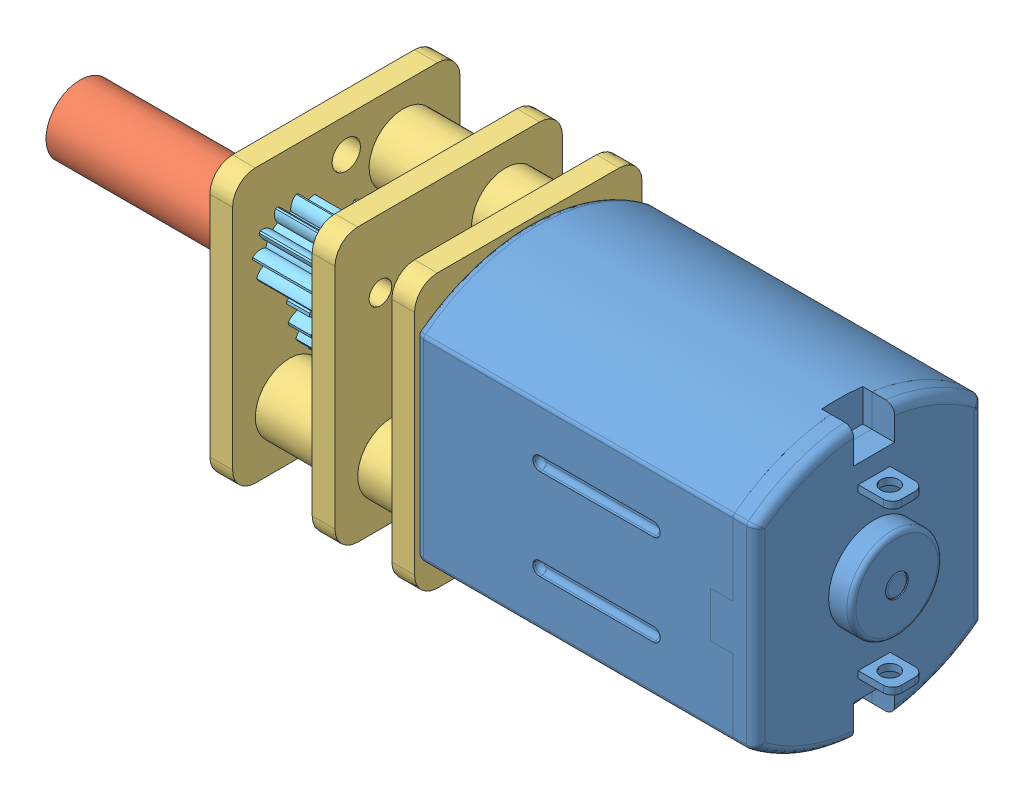
SolidWorks assembly Motor, configuration 轴长10mm. Lengths in mm.
Overall size (36.2 12.14 10.87).
11 component instances, 5 part files, 21 mates.
Components (placement in the parent):
- motor-1: motor [默认] at (-3.4114 0.0905 -5.0483)
- n20_shaft-1: n20_shaft [10mm] at (-13.1114 0.0905 -0.0483) x (0 -0.096252 -0.995357) z (0 0.995357 -0.096252) size (3 12 3)
- n20_gearbox-1: n20_gearbox [默认] at (-11.4114 0.0905 -0.0483) x (0 1 0) z (-1 0 0)
- cross recessed countersunk head screws gb1-1: cross recessed countersunk head screws gb1 [GB_CROSS_SCREWS_TYPE4 M1.6X3-2  H type-N] at (-12.4614 -3.4095 2.4517)
- cross recessed countersunk head screws gb1-2: cross recessed countersunk head screws gb1 [GB_CROSS_SCREWS_TYPE4 M1.6X3-2  H type-N] at (-12.4614 3.5905 -2.5483) x (1 0 0) z (0 0.116872 0.993147)
- spur gear_gb-1: spur gear_gb [GB - Spur gear 0.25M 10T 20PA 2FW ---S10A75H50L1.0N] at (-8.4114 -2.9095 -2.5483) x (1 0 0) z (0 -0.845955 0.533254)
- spur gear_gb-2: spur gear_gb [GB - Spur gear 0.25M 10T 20PA 2FW ---S10A75H50L1.0N] at (-4.4114 0.0905 -0.0483) x (-1 0 0) z (0 0.404067 -0.914729)
- spur gear_gb-4: spur gear_gb [GB - Spur gear 0.25M 16T 20PA 2FW ---S16A75H50L1.0N] at (-6.4114 -2.9095 -2.5483) x (1 0 0) z (0 -0.712706 0.701463)
- spur gear_gb-6: spur gear_gb [GB - Spur gear 0.25M 19T 20PA 2FW ---S19A75H50L1.0N] at (-9.9114 0.0905 -0.0483) x (1 0 0) z (0 0.321468 -0.94692)
- spur gear_gb-8: spur gear_gb [GB - Spur gear 0.25M 11T 20PA 3FW ---S11A75H50L1.0N] at (-10.9114 3.0905 2.9517) x (1 0 0) z (0 -0.604063 0.796937)
- spur gear_gb-10: spur gear_gb [GB - Spur gear 0.25M 19T 20PA 1FW ---S19A75H50L1.0N] at (-11.4114 0.0905 -0.0483) x (1 0 0) z (0 -0.330889 0.94367)
Mates (geometry in assembly coordinates):
- 同心1: concentric anti-aligned: cylinder of motor-1 through (-6.4114 0.0905 -0.0483) axis (1 0 0) radius 1; cylinder of n20_gearbox-1 through (-3.4114 0.0905 -0.0483) axis (-1 0 0) radius 0.5329
- 重合1: coincident anti-aligned: plane of motor-1 through (-3.4114 -5.9095 4.9517) normal (-1 0 0); plane of n20_gearbox-1 through (-3.4114 0.0905 -0.0483) normal (1 0 0)
- 重合2: coincident aligned: plane of motor-1 through (-3.4114 0.0905 4.9517) normal (0 0 1); plane of n20_gearbox-1 through (-3.4114 6.0905 4.9517) normal (0 0 1)
- 同心2: concentric aligned: cylinder of n20_shaft-1 through (-23.1114 0.0905 -0.0483) axis (1 0 0) radius 1.5; cylinder of n20_gearbox-1 through (-12.4114 0.0905 -0.0483) axis (1 0 0) radius 1.5
- 同心3: concentric anti-aligned: cone of n20_gearbox-1 through (-7.9114 3.5905 -2.5483) axis (-1 0 0); cylinder of cross recessed countersunk head screws gb1-2 through (-11.4614 3.5905 -2.5483) axis (1 0 0) radius 785.3982
- 重合4: coincident aligned: cone of n20_gearbox-1 through (-12.4114 3.5905 -2.5483) axis (1 0 0); cone of cross recessed countersunk head screws gb1-2 through (-11.4614 3.5905 -2.5483) axis (1 0 0)
- 同心8: concentric anti-aligned: cylinder of n20_gearbox-1 through (-7.9114 -3.4095 2.4517) axis (-1 0 0) radius 0.9; cylinder of cross recessed countersunk head screws gb1-1 through (-7.9456 -3.4095 2.4517) axis (1 0 0) radius 0.8
- 重合5: coincident aligned: cone of n20_gearbox-1 through (-12.4114 -3.4095 2.4517) axis (1 0 0); cone of cross recessed countersunk head screws gb1-1 through (-11.4614 -3.4095 2.4517) axis (1 0 0)
- 同心10: concentric aligned: cylinder of motor-1 through (-6.4114 0.0905 -0.0483) axis (1 0 0) radius 1; cylinder of spur gear_gb-2 through (-54.4115 0.0905 -0.0483) axis (1 0 0) radius 0.5
- 同心11: concentric aligned: cylinder of n20_gearbox-1 through (-3.4114 -2.9095 -2.5483) axis (-1 0 0) radius 0.5; cylinder of spur gear_gb-4 through (43.5886 -2.9095 -2.5483) axis (-1 0 0) radius 0.5
- 重合6: coincident anti-aligned: plane of n20_gearbox-1 through (-4.4114 0.0905 -0.0483) normal (-1 0 0); plane of spur gear_gb-4 through (-4.4114 -2.9095 -2.5483) normal (1 0 0)
- 同心12: concentric aligned: cylinder of n20_gearbox-1 through (-6.9114 0.0905 -0.0483) axis (-1 0 0) radius 0.5; cylinder of spur gear_gb-6 through (40.0886 0.0905 -0.0483) axis (-1 0 0) radius 0.5
- 重合7: coincident anti-aligned: plane of n20_gearbox-1 through (-7.9114 0.0905 -0.0483) normal (-1 0 0); plane of spur gear_gb-6 through (-7.9114 0.0905 -0.0483) normal (1 0 0)
- 同心13: concentric aligned: cylinder of spur gear_gb-1 through (41.5886 -2.9095 -2.5483) axis (-1 0 0) radius 0.5; cylinder of spur gear_gb-4 through (43.5886 -2.9095 -2.5483) axis (-1 0 0) radius 0.5
- 重合8: coincident anti-aligned: plane of spur gear_gb-1 through (-6.4114 -2.9095 -2.5483) normal (1 0 0); plane of spur gear_gb-4 through (-6.4114 -2.9095 -2.5483) normal (-1 0 0)
- 同心14: concentric aligned: cylinder of n20_gearbox-1 through (-6.9114 3.0905 2.9517) axis (-1 0 0) radius 0.5; cylinder of spur gear_gb-8 through (39.0886 3.0905 2.9517) axis (-1 0 0) radius 0.5
- 同心15: concentric aligned: cylinder of spur gear_gb-6 through (40.0886 0.0905 -0.0483) axis (-1 0 0) radius 0.5; cylinder of spur gear_gb-10 through (38.5886 0.0905 -0.0483) axis (-1 0 0) radius 0.5
- 重合9: coincident anti-aligned: plane of n20_gearbox-1 through (-7.9114 0.0905 -0.0483) normal (-1 0 0); plane of spur gear_gb-8 through (-7.9114 3.0905 2.9517) normal (1 0 0)
- 重合10: coincident anti-aligned: plane of n20_gearbox-1 through (-11.4114 0.0905 -0.0483) normal (1 0 0); plane of spur gear_gb-10 through (-11.4114 0.0905 -0.0483) normal (-1 0 0)
- 重合11: coincident anti-aligned: plane of n20_gearbox-1 through (-4.4114 0.0905 -0.0483) normal (-1 0 0); plane of spur gear_gb-2 through (-4.4114 0.0905 -0.0483) normal (1 0 0)
- Coincident2: coincident aligned: plane of n20_shaft-1 through (-13.1114 0.0905 -0.0483) normal (-1 0 0); plane of n20_gearbox-1 through (-13.1114 0.0905 -0.0483) normal (-1 0 0)
